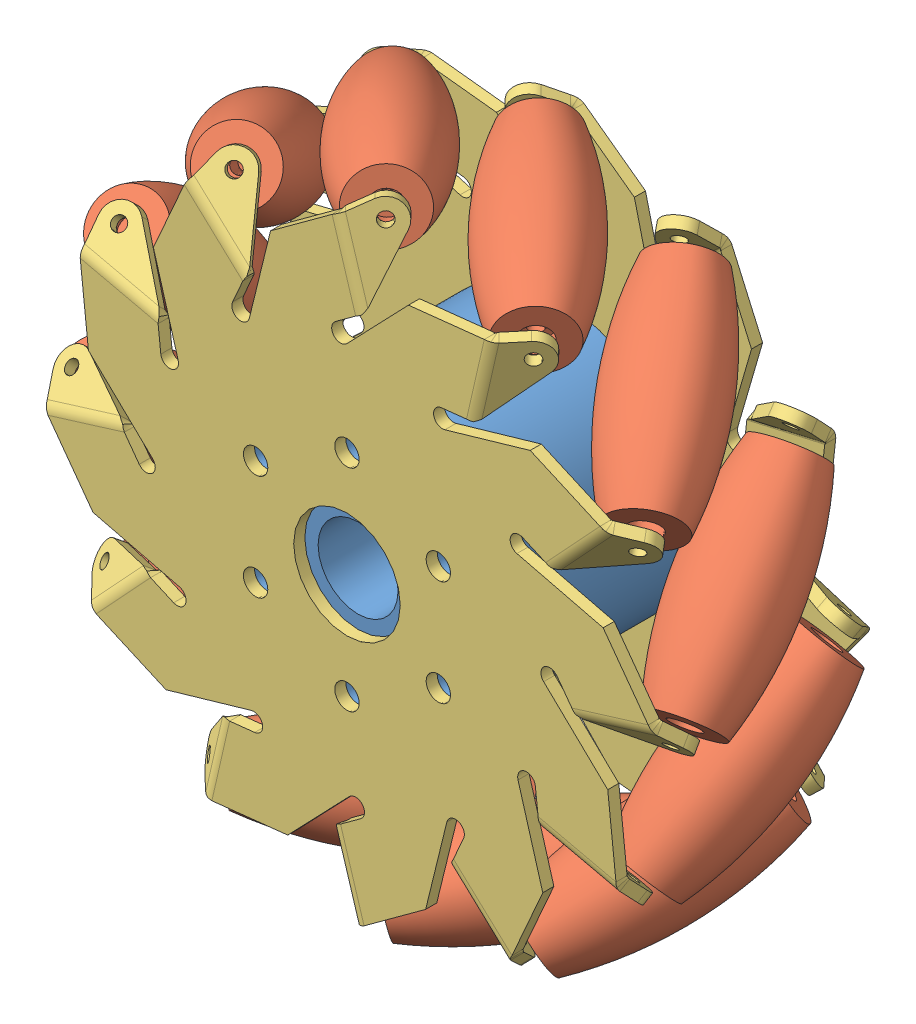
SolidWorks assembly Mecanum-Wheel2, configuration Default. Lengths in mm.
Overall size (160 160 52.36).
15 component instances, 3 part files, 11 mates.
Components (placement in the parent):
- Verbindungsstück-1: Verbindungsstück [Default] x (-1 0 0) z (0 0 -1) size (60 60 45)
- Roller-1: Roller [Default] at (0.1603 67.3643 -6.2343) x (-0.675708 -0.208372 -0.707107) z (0.723913 -0.006473 -0.689861) size (47.5 22.21 22.21)
- Blechbiegeteil2-1: Blechbiegeteil2 [Default] at (0 0 2.5) size (142.69 142.69 9.8)
- Blechbiegeteil2-2: Blechbiegeteil2 [Default] at (0 0 -47.5) x (-1 0 0) z (0 0 -1) size (142.69 142.69 9.8)
- Roller-13: Roller [Default] at (-33.5433 58.4194 -6.2343) x (-0.480994 -0.51831 -0.707107) z (0.630164 0.356351 -0.689861) size (47.5 22.21 22.21)
- Roller-14: Roller [Default] at (-58.2591 33.821 -6.2343) x (-0.157398 -0.689366 -0.707107) z (0.367562 0.623691 -0.689861) size (47.5 22.21 22.21)
- Roller-15: Roller [Default] at (-67.3643 0.1603 -6.2343) x (0.208372 -0.675708 -0.707107) z (0.006473 0.723913 -0.689861) size (47.5 22.21 22.21)
- Roller-16: Roller [Default] at (-58.4194 -33.5433 -6.2343) x (0.51831 -0.480994 -0.707107) z (-0.356351 0.630164 -0.689861) size (47.5 22.21 22.21)
- Roller-17: Roller [Default] at (-33.821 -58.2591 -6.2343) x (0.689366 -0.157398 -0.707107) z (-0.623691 0.367562 -0.689861) size (47.5 22.21 22.21)
- Roller-18: Roller [Default] at (-0.1603 -67.3643 -6.2343) x (0.675708 0.208372 -0.707107) z (-0.723913 0.006473 -0.689861) size (47.5 22.21 22.21)
- Roller-19: Roller [Default] at (33.5433 -58.4194 -6.2343) x (0.480994 0.51831 -0.707107) z (-0.630164 -0.356351 -0.689861) size (47.5 22.21 22.21)
- Roller-20: Roller [Default] at (58.2591 -33.821 -6.2343) x (0.157398 0.689366 -0.707107) z (-0.367562 -0.623691 -0.689861) size (47.5 22.21 22.21)
- Roller-21: Roller [Default] at (67.3643 -0.1603 -6.2343) x (-0.208372 0.675708 -0.707107) z (-0.006473 -0.723913 -0.689861) size (47.5 22.21 22.21)
- Roller-22: Roller [Default] at (58.4194 33.5433 -6.2343) x (-0.51831 0.480994 -0.707107) z (0.356351 -0.630164 -0.689861) size (47.5 22.21 22.21)
- Roller-23: Roller [Default] at (33.821 58.2591 -6.2343) x (-0.689366 0.157398 -0.707107) z (0.623691 -0.367562 -0.689861) size (47.5 22.21 22.21)
Mates (geometry in assembly coordinates):
- Coincident2: coincident aligned: plane of Verbindungsstück-1 through (0 0 0) normal (0 1 0)
- Coincident3: coincident anti-aligned: plane of Verbindungsstück-1 through (0 0 0) normal (-1 0 0)
- Coincident4: coincident anti-aligned: plane of Verbindungsstück-1 through (0 0 0) normal (0 0 -1)
- Concentric1: concentric anti-aligned: cylinder of Verbindungsstück-1 through (0 0 -45) axis (0 0 1) radius 9; cylinder of Blechbiegeteil2-1 through (0 0 2.5073) axis (0 0 -1) radius 12
- Concentric2: concentric aligned: cylinder of Verbindungsstück-1 through (20.5681 11.875 -45) axis (0 0 -1) radius 2.75; cylinder of Blechbiegeteil2-1 through (20.5681 11.875 0) axis (0 0 -1) radius 2.75
- Coincident5: coincident anti-aligned: plane of Verbindungsstück-1 through (0 0 0) normal (0 0 1); plane of Blechbiegeteil2-1 through (-1.4433 46.3845 0) normal (0 0 -1)
- Concentric3: concentric aligned: cylinder of Roller-1 through (0.1603 67.3643 -6.2343) axis (0.675708 0.208372 0.707107) radius 3.25; cylinder of Blechbiegeteil2-1 through (1.8496 67.8853 -4.4666) axis (0.675708 0.208372 0.707107) radius 1.5
- Coincident6: coincident anti-aligned: plane of Verbindungsstück-1 through (0 0 -45) normal (0 0 -1); plane of Blechbiegeteil2-2 through (1.4433 46.3845 -45) normal (0 0 1)
- Concentric4: concentric aligned: cylinder of Verbindungsstück-1 through (0 0 -45) axis (0 0 1) radius 9; cylinder of Blechbiegeteil2-2 through (0 0 -47.5073) axis (0 0 1) radius 12
- Concentric5: concentric anti-aligned: cylinder of Verbindungsstück-1 through (0 23.75 -45) axis (0 0 -1) radius 2.75; cylinder of Blechbiegeteil2-2 through (0 23.75 -45) axis (0 0 1) radius 2.75
- Distance2: distance = 2.5 mm anti-aligned: plane of Roller-1 through (0.1603 67.3643 -6.2343) normal (0.675708 0.208372 0.707107); plane of Blechbiegeteil2-1 through (-0.6814 46.6195 4.2186) normal (-0.675708 -0.208372 -0.707107)
